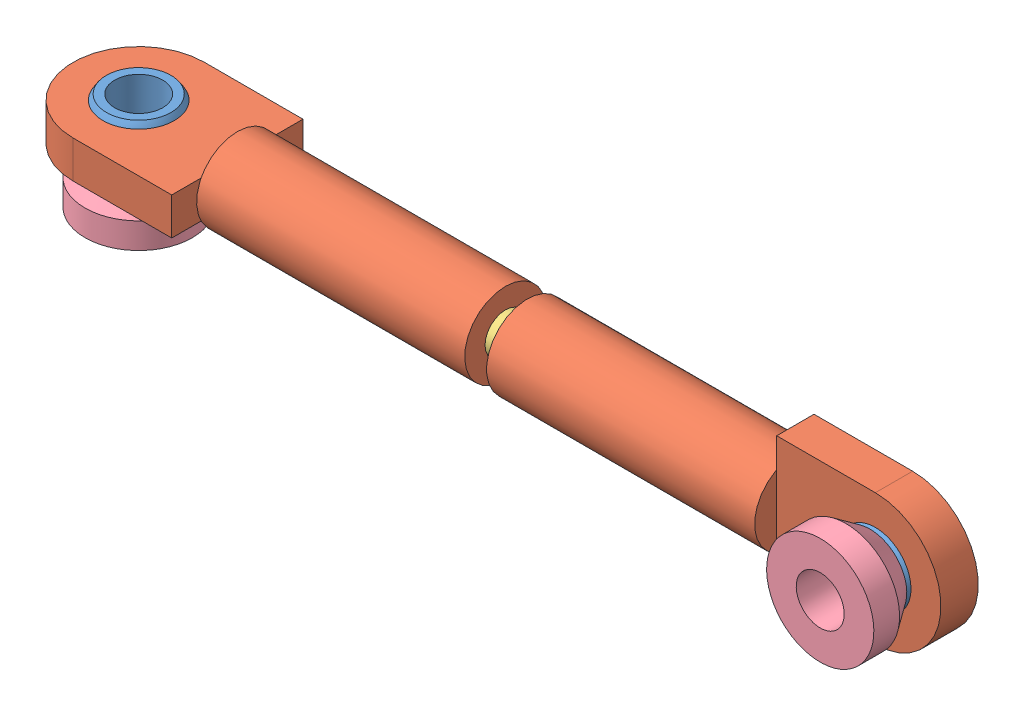
SolidWorks assembly 4-40_Ball_Joint_Asm, configuration Default. Lengths in mm.
Overall size (52.76 8.52 8.26).
7 component instances, 4 part files, 10 mates.
Components (placement in the parent):
- 4-40_Ball_Joint_Half_Sphere-1: 4-40_Ball_Joint_Half_Sphere [Default] at (0.0786 0.1841 0.4617) size (4.76 4.76 2.84)
- 4-40_Ball_Joint_Plastic-1: 4-40_Ball_Joint_Plastic [Default] at (0.0786 0.1841 0.4617) size (25.6 7.77 4.83)
- 4-40_Ball_Joint_Plastic-3: 4-40_Ball_Joint_Plastic [Default] at (-44.6508 0.1841 0.4617) x (-1 0 0) z (0 -1 0) size (25.6 7.77 4.83)
- 4-40_Ball_Joint_Half_Sphere-2: 4-40_Ball_Joint_Half_Sphere [Default] at (-44.6508 0.1841 0.4617) x (-1 0 0) z (0 -1 0) size (4.76 4.76 2.84)
- 4-40_Threaded_Rod-1: 4-40_Threaded_Rod [Default] at (-9.5734 0.1841 0.4617) x (0 0 1) z (-1 0 0) size (2.41 2.41 26.7)
- 4-40_Ball_Joint_Base-1: 4-40_Ball_Joint_Base [Default] at (-44.6508 -4.1847 0.4617) x (1 0 0) z (0 1 0) size (6.35 6.35 2.95)
- 4-40_Ball_Joint_Base-2: 4-40_Ball_Joint_Base [Default] at (0.0786 0.1841 4.8305) x (-0.923728 -0.383049 0) z (0 0 -1) size (6.35 6.35 2.95)
Mates (geometry in assembly coordinates):
- Coincident1: coordinate: point of 4-40_Ball_Joint_Half_Sphere-1; point of 4-40_Ball_Joint_Plastic-1
- Coincident2: coordinate: point of 4-40_Ball_Joint_Plastic-3; point of 4-40_Ball_Joint_Half_Sphere-2
- Coincident3: coincident anti-aligned: axis of 4-40_Ball_Joint_Plastic-3 through (-21.6638 0.1841 0.4617) axis (-1 0 0); axis of 4-40_Threaded_Rod-1 through (-34.9988 0.1841 0.4617) axis (1 0 0)
- Coincident4: coincident aligned: axis of 4-40_Ball_Joint_Plastic-1 through (-21.6384 0.1841 0.4617) axis (1 0 0); axis of 4-40_Threaded_Rod-1 through (-34.9988 0.1841 0.4617) axis (1 0 0)
- Distance1: distance = 3.81 mm anti-aligned: plane of 4-40_Threaded_Rod-1 through (-9.5734 0.1841 0.4617) normal (1 0 0); plane of 4-40_Ball_Joint_Plastic-1 through (-5.7634 4.0703 -0.6432) normal (-1 0 0)
- Distance3: distance = 2.54 mm anti-aligned: plane of 4-40_Threaded_Rod-1 through (-36.2688 0.1841 0.4617) normal (-1 0 0); plane of 4-40_Ball_Joint_Plastic-3 through (-38.8088 1.289 -3.4245) normal (1 0 0)
- Coincident8: coincident: axis of 4-40_Ball_Joint_Base-1 through (-44.6508 -13.1345 0.4617) axis (0 1 0); axis of 4-40_Ball_Joint_Half_Sphere-2 through (-44.6508 -1.2383 0.4617) axis (0 1 0)
- Distance4: distance = 0 mm anti-aligned: plane of 4-40_Ball_Joint_Half_Sphere-2 through (-44.6508 -1.2383 0.4617) normal (0 -1 0); plane of 4-40_Ball_Joint_Base-1 through (-44.6508 -1.2383 0.4617) normal (0 1 0)
- Coincident10: coincident: axis of 4-40_Ball_Joint_Base-2 through (0.0786 0.1841 6.3122) axis (0 0 1); axis of 4-40_Ball_Joint_Half_Sphere-1 through (0.0786 0.1841 1.8841) axis (0 0 -1)
- Distance6: distance = 0 mm anti-aligned: plane of 4-40_Ball_Joint_Half_Sphere-1 through (0.0786 0.1841 1.8841) normal (0 0 1); plane of 4-40_Ball_Joint_Base-2 through (0.0786 0.1841 1.8841) normal (0 0 -1)
